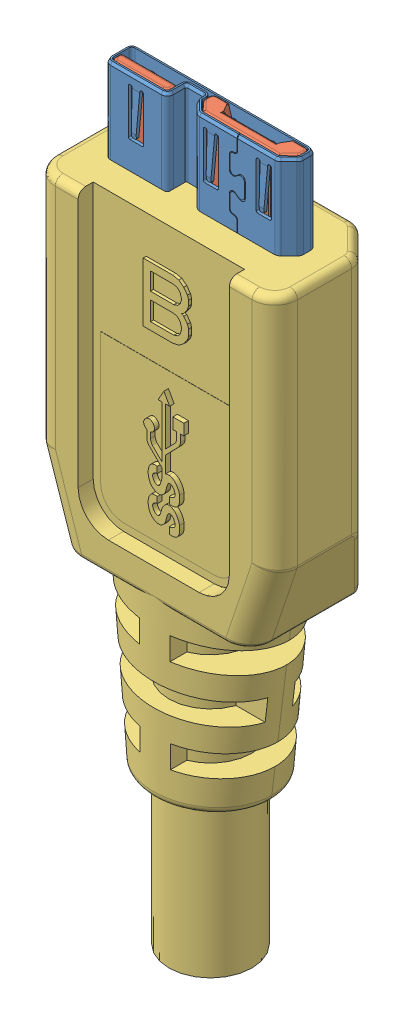
SolidWorks assembly ZX360-B, configuration 00. Lengths in mm.
Overall size (16.04 48.1 7.71).
3 component instances, 3 part files, 7 mates.
Components (placement in the parent):
- ZX360-B-SLDA^ZX360-B-1: ZX360-B-SLDA^ZX360-B [00] at (0 0 -2.15) size (13.45 23.42 3.35) (virtual)
- ZX360-B-10S-UNIT^ZX360-B-1: ZX360-B-10S-UNIT^ZX360-B [00] at (-0.3638 2.6 -0.7) x (1 0 0) z (0 1 0) size (13.45 4.2 14.85) (virtual)
- RR-MSAFPM-XXGR^ZX360-B-1: RR-MSAFPM-XXGR^ZX360-B [00] at (0 3.45 0) size (16.04 42.5 7.71) (virtual)
Mates (geometry in assembly coordinates):
- Симметричный1: symmetric aligned: plane of ZX360-B-SLDA^ZX360-B-1 through (6.0048 2.7314 -0.9) normal (0 0 -1); plane of ZX360-B-SLDA^ZX360-B-1 through (3.2438 9.0748 0.9) normal (0 0 1); plane of assembly through (0 0 0) normal (0 0 1)
- Совпадение3: coincident anti-aligned: plane of ZX360-B-SLDA^ZX360-B-1 through (-2.2464 9.2623 0.7) normal (0 0 -1); plane of ZX360-B-10S-UNIT^ZX360-B-1 through (-5.6585 9.1016 0.7) normal (0 0 1)
- Симметричный2: symmetric aligned: plane of ZX360-B-SLDA^ZX360-B-1 through (0 0 -2.15) normal (1 0 0); plane of ZX360-B-10S-UNIT^ZX360-B-1 through (6.475 2.8166 -1.7416) normal (1 0 0); plane of ZX360-B-10S-UNIT^ZX360-B-1 through (-6.475 2.8166 1.8416) normal (-1 0 0)
- Совпадение4: coincident anti-aligned: plane of ZX360-B-SLDA^ZX360-B-1 through (6.1342 3.05 -0.4189) normal (0 -1 0); plane of ZX360-B-10S-UNIT^ZX360-B-1 through (5.5303 3.05 -1.0691) normal (0 1 0)
- Совпадение6: coincident aligned: plane of ZX360-B-SLDA^ZX360-B-1 through (0 0 -2.15) normal (1 0 0); plane of RR-MSAFPM-XXGR^ZX360-B-1 through (0 3.45 0) normal (1 0 0)
- Симметричный3: symmetric aligned: plane of ZX360-B-SLDA^ZX360-B-1 through (6.0048 2.7314 -0.9) normal (0 0 -1); plane of ZX360-B-SLDA^ZX360-B-1 through (-2.2464 9.0623 0.9) normal (0 0 1); plane of RR-MSAFPM-XXGR^ZX360-B-1 through (0 3.45 0) normal (0 0 1)
- Расстояние1: distance = 5.6 mm aligned: plane of ZX360-B-SLDA^ZX360-B-1 through (6.3198 9.05 0.8598) normal (0 1 0); plane of RR-MSAFPM-XXGR^ZX360-B-1 through (0 3.45 0) normal (0 1 0)
